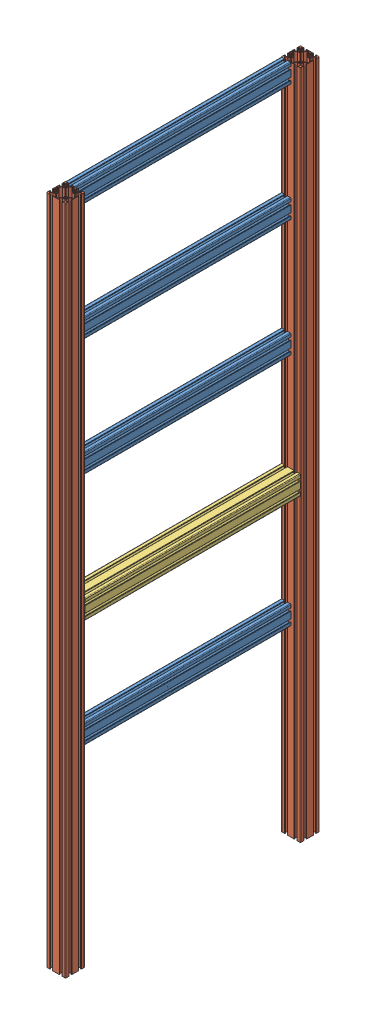
SolidWorks assembly Frame V3 Front_or_Back, configuration Default. Lengths in mm.
Overall size (40 1400 530).
7 component instances, 3 part files, 18 mates.
Components (placement in the parent):
- 20_2040_450_CL-1: 20_2040_450_CL [Default] at (841.1716 1609.6814 362.4928) size (20 40 450)
- 20_2040_450_CL-2: 20_2040_450_CL [Default] at (841.1716 1364.9814 362.4928) size (20 40 450)
- 20_2040_450_CL-3: 20_2040_450_CL [Default] at (841.1716 1120.2814 362.4928) size (20 40 450)
- 20_4040_1400_CL-1: 20_4040_1400_CL [Default] at (851.1716 239.6814 372.4928) x (1 0 0) z (0 -1 0) size (40 40 1400)
- 20_4040_1400_CL-2: 20_4040_1400_CL [Default] at (851.1716 239.6814 -117.5072) x (1 0 0) z (0 -1 0) size (40 40 1400)
- 20_2040_450_CL-5: 20_2040_450_CL [Default] at (841.1716 630.8814 362.4928) size (20 40 450)
- 20_4040_450_CL-1: 20_4040_450_CL [Default] at (851.1716 875.5814 362.4928) size (40 40 450)
Mates (geometry in assembly coordinates):
- Distance1: distance = 204.7 mm anti-aligned: plane of 20_2040_450_CL-2 through (838.0336 1394.9814 -87.5072) normal (0 1 0); plane of 20_2040_450_CL-1 through (832.6716 1599.6814 -87.5072) normal (0 -1 0)
- Distance2: distance = 204.7 mm anti-aligned: plane of 20_2040_450_CL-3 through (838.0336 1150.2814 -87.5072) normal (0 1 0); plane of 20_2040_450_CL-2 through (832.6716 1354.9814 -87.5072) normal (0 -1 0)
- Coincident13: coincident anti-aligned: plane of 20_2040_450_CL-1 through (832.6716 1638.1814 362.4928) normal (0 0 1); plane of 20_4040_1400_CL-1 through (844.3096 1639.6814 362.4928) normal (0 0 -1)
- Coincident14: coincident aligned: plane of 20_2040_450_CL-1 through (831.1716 1626.5434 -87.5072) normal (-1 0 0); plane of 20_4040_1400_CL-1 through (831.1716 1639.6814 369.3548) normal (-1 0 0)
- Coincident15: coincident aligned: plane of 20_2040_450_CL-1 through (838.0336 1639.6814 -87.5072) normal (0 1 0); plane of 20_4040_1400_CL-1 through (832.6716 1639.6814 400.9928) normal (0 1 0)
- Coincident16: coincident aligned: plane of 20_2040_450_CL-2 through (831.1716 1381.8434 -87.5072) normal (-1 0 0); plane of 20_4040_1400_CL-1 through (831.1716 1639.6814 369.3548) normal (-1 0 0)
- Coincident17: coincident anti-aligned: plane of 20_2040_450_CL-2 through (832.6716 1393.4814 362.4928) normal (0 0 1); plane of 20_4040_1400_CL-1 through (844.3096 1639.6814 362.4928) normal (0 0 -1)
- Coincident18: coincident aligned: plane of 20_2040_450_CL-3 through (831.1716 1137.1434 -87.5072) normal (-1 0 0); plane of 20_4040_1400_CL-1 through (831.1716 1639.6814 389.3548) normal (-1 0 0)
- Coincident19: coincident anti-aligned: plane of 20_2040_450_CL-3 through (832.6716 1148.7814 362.4928) normal (0 0 1); plane of 20_4040_1400_CL-1 through (844.3096 1639.6814 362.4928) normal (0 0 -1)
- Coincident20: coincident anti-aligned: plane of 20_2040_450_CL-1 through (832.6716 1638.1814 -87.5072) normal (0 0 -1); plane of 20_4040_1400_CL-2 through (858.0336 1639.6814 -87.5072) normal (0 0 1)
- Coincident21: coincident aligned: plane of 20_2040_450_CL-1 through (831.1716 1626.5434 -87.5072) normal (-1 0 0); plane of 20_4040_1400_CL-2 through (831.1716 1639.6814 -100.6452) normal (-1 0 0)
- Coincident22: coincident aligned: plane of 20_2040_450_CL-1 through (838.0336 1639.6814 -87.5072) normal (0 1 0); plane of 20_4040_1400_CL-2 through (832.6716 1639.6814 -89.0072) normal (0 1 0)
- Coincident27: coincident anti-aligned: plane of 20_4040_1400_CL-2 through (858.0336 1639.6814 -87.5072) normal (0 0 1); plane of 20_2040_450_CL-5 through (832.6716 659.3814 -87.5072) normal (0 0 -1)
- Coincident28: coincident aligned: plane of 20_4040_1400_CL-2 through (831.1716 1639.6814 -100.6452) normal (-1 0 0); plane of 20_2040_450_CL-5 through (831.1716 647.7434 -87.5072) normal (-1 0 0)
- Coincident30: coincident anti-aligned: plane of 20_4040_1400_CL-1 through (844.3096 1639.6814 362.4928) normal (0 0 -1); plane of 20_4040_450_CL-1 through (832.6716 904.0814 362.4928) normal (0 0 1)
- Coincident31: coincident aligned: plane of 20_4040_1400_CL-1 through (871.1716 1639.6814 375.6308) normal (1 0 0); plane of 20_4040_450_CL-1 through (871.1716 878.7194 -87.5072) normal (1 0 0)
- Distance6: distance = 204.7 mm anti-aligned: plane of 20_4040_450_CL-1 through (838.0336 905.5814 -87.5072) normal (0 1 0); plane of 20_2040_450_CL-3 through (832.6716 1110.2814 -87.5072) normal (0 -1 0)
- Distance7: distance = 204.7 mm anti-aligned: plane of 20_2040_450_CL-5 through (838.0336 660.8814 -87.5072) normal (0 1 0); plane of 20_4040_450_CL-1 through (832.6716 865.5814 -87.5072) normal (0 -1 0)
